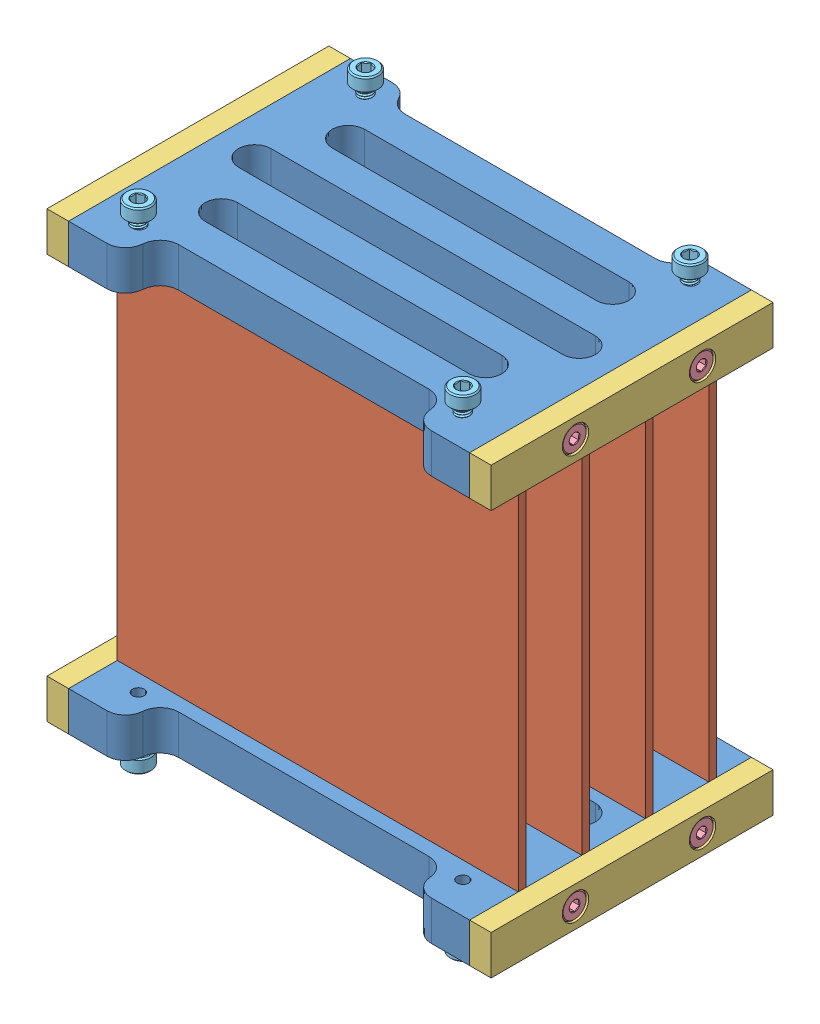
SolidWorks assembly STACK_SHELVES_ASSEMBLY, configuration Default. Lengths in mm.
Overall size (95.8 106.09 60.8).
26 component instances, 5 part files, 36 mates.
Components (placement in the parent):
- PCB_SHELF-1: PCB_SHELF [Default] at (-4.1696 1.9377 23.7027) x (0 1 0) z (1 0 0) size (8.5 60.8 86.5)
- FAKE_PCB-1: FAKE_PCB [Default] at (82.3304 4.4377 31.2027) x (0 1 0) z (1 0 0) size (91 1.7 86.5)
- FAKE_PCB-2: FAKE_PCB [Default] at (82.3304 4.4377 44.9027) x (0 1 0) z (1 0 0) size (91 1.7 86.5)
- FAKE_PCB-3: FAKE_PCB [Default] at (82.3304 4.4377 58.6027) x (0 1 0) z (1 0 0) size (91 1.7 86.5)
- FAKE_PCB-4: FAKE_PCB [Default] at (82.3304 4.3377 72.3027) x (0 1 0) z (1 0 0) size (91 1.7 86.5)
- PCB_SHELF-2: PCB_SHELF [Default] at (82.3304 97.7377 23.7027) x (0 -1 0) z (-1 0 0) size (8.5 60.8 86.5)
- PCB_SHELF_ENDS-1: PCB_SHELF_ENDS [Default] at (-4.1696 97.7377 84.5027) x (0 -1 0) z (-1 0 0) size (8.5 60.8 4.65)
- PCB_SHELF_ENDS-2: PCB_SHELF_ENDS [Default] at (-4.1696 10.4377 84.5027) x (0 -1 0) z (-1 0 0) size (8.5 60.8 4.65)
- PCB_SHELF_ENDS-3: PCB_SHELF_ENDS [Default] at (82.3304 89.2377 84.5027) x (0 1 0) z (1 0 0) size (8.5 60.8 4.65)
- PCB_SHELF_ENDS-4: PCB_SHELF_ENDS [Default] at (82.3304 1.9377 84.5027) x (0 1 0) z (1 0 0) size (8.5 60.8 4.65)
- M3_LP_6MM_90666A103_TYPE 316 SS LOW PROFILE SOCKET HEAD CAP SCREW-1: M3_LP_6MM_90666A103_TYPE 316 SS LOW PROFILE SOCKET HEAD CAP SCREW [90666A103] at (78.7804 6.1877 66.3027) x (0 -0.137884 0.990448) z (-1 0 0) size (5.5 5.5 8.16)
- M3_6MM_91292A111_TYPE 18-8 SS SOCKET HEAD CAP SCREW-1: M3_6MM_91292A111_TYPE 18-8 SS SOCKET HEAD CAP SCREW [91292A111] at (74.0804 93.7377 77.7027) x (0.999989 0 -0.00475) z (0 -1 0) size (5.5 5.5 9.19)
- M3_LP_6MM_90666A103_TYPE 316 SS LOW PROFILE SOCKET HEAD CAP SCREW-9: M3_LP_6MM_90666A103_TYPE 316 SS LOW PROFILE SOCKET HEAD CAP SCREW [90666A103] at (78.7804 6.1877 38.9027) x (0 0 1) z (-1 0 0) size (5.5 5.5 8.16)
- M3_LP_6MM_90666A103_TYPE 316 SS LOW PROFILE SOCKET HEAD CAP SCREW-3: M3_LP_6MM_90666A103_TYPE 316 SS LOW PROFILE SOCKET HEAD CAP SCREW [90666A103] at (78.7804 93.4877 66.3027) x (0 0.137884 0.990448) z (-1 0 0) size (5.5 5.5 8.16)
- M3_LP_6MM_90666A103_TYPE 316 SS LOW PROFILE SOCKET HEAD CAP SCREW-5: M3_LP_6MM_90666A103_TYPE 316 SS LOW PROFILE SOCKET HEAD CAP SCREW [90666A103] at (-0.6196 6.1877 66.3027) x (0 -0.137884 0.990448) z (1 0 0) size (5.5 5.5 8.16)
- M3_LP_6MM_90666A103_TYPE 316 SS LOW PROFILE SOCKET HEAD CAP SCREW-7: M3_LP_6MM_90666A103_TYPE 316 SS LOW PROFILE SOCKET HEAD CAP SCREW [90666A103] at (-0.6196 93.4877 66.3027) x (0 0.137884 0.990448) z (1 0 0) size (5.5 5.5 8.16)
- M3_6MM_91292A111_TYPE 18-8 SS SOCKET HEAD CAP SCREW-3: M3_6MM_91292A111_TYPE 18-8 SS SOCKET HEAD CAP SCREW [91292A111] at (4.0804 93.7377 77.7027) x (-0.999989 0 -0.00475) z (0 -1 0) size (5.5 5.5 9.19)
- M3_6MM_91292A111_TYPE 18-8 SS SOCKET HEAD CAP SCREW-5: M3_6MM_91292A111_TYPE 18-8 SS SOCKET HEAD CAP SCREW [91292A111] at (74.0804 5.9377 77.7027) x (0.999989 0 -0.00475) z (0 1 0) size (5.5 5.5 9.19)
- M3_6MM_91292A111_TYPE 18-8 SS SOCKET HEAD CAP SCREW-7: M3_6MM_91292A111_TYPE 18-8 SS SOCKET HEAD CAP SCREW [91292A111] at (4.0804 5.9377 77.7027) x (-0.999989 0 -0.00475) z (0 1 0) size (5.5 5.5 9.19)
- M3_LP_6MM_90666A103_TYPE 316 SS LOW PROFILE SOCKET HEAD CAP SCREW-10: M3_LP_6MM_90666A103_TYPE 316 SS LOW PROFILE SOCKET HEAD CAP SCREW [90666A103] at (78.7804 93.4877 38.9027) x (0 0 1) z (-1 0 0) size (5.5 5.5 8.16)
- M3_LP_6MM_90666A103_TYPE 316 SS LOW PROFILE SOCKET HEAD CAP SCREW-11: M3_LP_6MM_90666A103_TYPE 316 SS LOW PROFILE SOCKET HEAD CAP SCREW [90666A103] at (-0.6196 6.1877 38.9027) x (0 0 1) z (1 0 0) size (5.5 5.5 8.16)
- M3_LP_6MM_90666A103_TYPE 316 SS LOW PROFILE SOCKET HEAD CAP SCREW-12: M3_LP_6MM_90666A103_TYPE 316 SS LOW PROFILE SOCKET HEAD CAP SCREW [90666A103] at (-0.6196 93.4877 38.9027) x (0 0 1) z (1 0 0) size (5.5 5.5 8.16)
- M3_6MM_91292A111_TYPE 18-8 SS SOCKET HEAD CAP SCREW-9: M3_6MM_91292A111_TYPE 18-8 SS SOCKET HEAD CAP SCREW [91292A111] at (74.0804 93.7377 28.7027) x (-0.982447 0 -0.186539) z (0 -1 0) size (5.5 5.5 9.19)
- M3_6MM_91292A111_TYPE 18-8 SS SOCKET HEAD CAP SCREW-10: M3_6MM_91292A111_TYPE 18-8 SS SOCKET HEAD CAP SCREW [91292A111] at (4.0804 93.7377 28.7027) x (0.982447 0 -0.186539) z (0 -1 0) size (5.5 5.5 9.19)
- M3_6MM_91292A111_TYPE 18-8 SS SOCKET HEAD CAP SCREW-11: M3_6MM_91292A111_TYPE 18-8 SS SOCKET HEAD CAP SCREW [91292A111] at (74.0804 5.9377 28.7027) x (-0.982447 0 -0.186539) z (0 1 0) size (5.5 5.5 9.19)
- M3_6MM_91292A111_TYPE 18-8 SS SOCKET HEAD CAP SCREW-12: M3_6MM_91292A111_TYPE 18-8 SS SOCKET HEAD CAP SCREW [91292A111] at (4.0804 -3.1627 28.7027) x (0.982447 0 -0.186539) z (0 -1 0) size (5.5 5.5 9.19)
Mates (geometry in assembly coordinates):
- Coincident10: coincident anti-aligned: plane of PCB_SHELF-1 through (82.3304 4.4377 32.9027) normal (0 1 0); plane of FAKE_PCB-1 through (82.3304 4.4377 32.9027) normal (0 -1 0)
- Coincident11: coincident anti-aligned: plane of PCB_SHELF-1 through (82.3304 4.4377 31.2027) normal (0 0 1); plane of FAKE_PCB-1 through (82.3304 4.4377 31.2027) normal (0 0 -1)
- Coincident12: coincident aligned: plane of PCB_SHELF-1 through (82.3304 1.9377 23.7027) normal (1 0 0); plane of FAKE_PCB-1 through (82.3304 95.4377 32.9027) normal (1 0 0)
- Coincident13: coincident anti-aligned: plane of PCB_SHELF-1 through (82.3304 4.4377 46.6027) normal (0 1 0); plane of FAKE_PCB-2 through (82.3304 4.4377 46.6027) normal (0 -1 0)
- Coincident14: coincident anti-aligned: plane of PCB_SHELF-1 through (82.3304 4.4377 44.9027) normal (0 0 1); plane of FAKE_PCB-2 through (82.3304 4.4377 44.9027) normal (0 0 -1)
- Coincident15: coincident aligned: plane of PCB_SHELF-1 through (-4.1696 1.9377 23.7027) normal (-1 0 0); plane of FAKE_PCB-2 through (-4.1696 4.4377 46.6027) normal (-1 0 0)
- Coincident16: coincident anti-aligned: plane of PCB_SHELF-1 through (82.3304 4.4377 60.3027) normal (0 1 0); plane of FAKE_PCB-3 through (82.3304 4.4377 60.3027) normal (0 -1 0)
- Coincident17: coincident anti-aligned: plane of PCB_SHELF-1 through (82.3304 4.4377 58.6027) normal (0 0 1); plane of FAKE_PCB-3 through (82.3304 4.4377 58.6027) normal (0 0 -1)
- Coincident18: coincident aligned: plane of PCB_SHELF-1 through (-4.1696 1.9377 23.7027) normal (-1 0 0); plane of FAKE_PCB-3 through (-4.1696 4.4377 60.3027) normal (-1 0 0)
- Coincident19: coincident anti-aligned: plane of PCB_SHELF-1 through (82.3304 4.3377 74.0027) normal (0 1 0); plane of FAKE_PCB-4 through (82.3304 4.3377 74.0027) normal (0 -1 0)
- Coincident20: coincident anti-aligned: plane of PCB_SHELF-1 through (82.3304 4.3377 72.3027) normal (0 0 1); plane of FAKE_PCB-4 through (82.3304 4.3377 72.3027) normal (0 0 -1)
- Coincident21: coincident aligned: plane of PCB_SHELF-1 through (-4.1696 1.9377 23.7027) normal (-1 0 0); plane of FAKE_PCB-4 through (-4.1696 4.3377 74.0027) normal (-1 0 0)
- Coincident22: coincident anti-aligned: plane of FAKE_PCB-4 through (-4.1696 95.3377 74.0027) normal (0 1 0); plane of PCB_SHELF-2 through (-4.1696 95.3377 74.0027) normal (0 -1 0)
- Coincident23: coincident aligned: plane of FAKE_PCB-4 through (82.3304 95.3377 74.0027) normal (1 0 0); plane of PCB_SHELF-2 through (82.3304 97.7377 23.7027) normal (1 0 0)
- Coincident24: coincident aligned: plane of FAKE_PCB-1 through (82.3304 95.4377 32.9027) normal (1 0 0); plane of PCB_SHELF-2 through (82.3304 97.7377 23.7027) normal (1 0 0)
- Coincident25: coincident anti-aligned: plane of FAKE_PCB-1 through (82.3304 4.4377 32.9027) normal (0 0 1); plane of PCB_SHELF-2 through (-4.1696 89.2377 32.9027) normal (0 0 -1)
- Concentric1: concentric aligned: cylinder of PCB_SHELF-1 through (82.3304 6.1877 66.3027) axis (1 0 0) radius 1.25; cylinder of PCB_SHELF_ENDS-4 through (86.9804 6.1877 66.3027) axis (1 0 0) radius 1.5
- Coincident26: coincident anti-aligned: plane of PCB_SHELF-1 through (82.3304 1.9377 23.7027) normal (1 0 0); plane of PCB_SHELF_ENDS-4 through (82.3304 1.9377 84.5027) normal (-1 0 0)
- Concentric2: concentric aligned: cylinder of PCB_SHELF-1 through (82.3304 6.1877 38.9027) axis (1 0 0) radius 1.25; cylinder of PCB_SHELF_ENDS-4 through (86.9804 6.1877 38.9027) axis (1 0 0) radius 1.5
- Coincident27: coincident anti-aligned: plane of PCB_SHELF-2 through (82.3304 97.7377 23.7027) normal (1 0 0); plane of PCB_SHELF_ENDS-3 through (82.3304 89.2377 84.5027) normal (-1 0 0)
- Concentric3: concentric aligned: cylinder of PCB_SHELF-2 through (82.3304 93.4877 66.3027) axis (1 0 0) radius 1.25; cylinder of PCB_SHELF_ENDS-3 through (86.9804 93.4877 66.3027) axis (1 0 0) radius 1.5
- Concentric4: concentric aligned: cylinder of PCB_SHELF-2 through (82.3304 93.4877 38.9027) axis (1 0 0) radius 1.25; cylinder of PCB_SHELF_ENDS-3 through (86.9804 93.4877 38.9027) axis (1 0 0) radius 1.5
- Coincident28: coincident anti-aligned: plane of PCB_SHELF-1 through (-4.1696 1.9377 23.7027) normal (-1 0 0); plane of PCB_SHELF_ENDS-2 through (-4.1696 10.4377 84.5027) normal (1 0 0)
- Concentric5: concentric aligned: cylinder of PCB_SHELF-1 through (-4.1696 6.1877 66.3027) axis (-1 0 0) radius 1.25; cylinder of PCB_SHELF_ENDS-2 through (-8.8196 6.1877 66.3027) axis (-1 0 0) radius 1.5
- Concentric6: concentric aligned: cylinder of PCB_SHELF-1 through (-4.1696 6.1877 38.9027) axis (-1 0 0) radius 1.25; cylinder of PCB_SHELF_ENDS-2 through (-8.8196 6.1877 38.9027) axis (-1 0 0) radius 1.5
- Coincident29: coincident anti-aligned: plane of PCB_SHELF-2 through (-4.1696 97.7377 23.7027) normal (-1 0 0); plane of PCB_SHELF_ENDS-1 through (-4.1696 97.7377 84.5027) normal (1 0 0)
- Concentric7: concentric aligned: cylinder of PCB_SHELF-2 through (-4.1696 93.4877 66.3027) axis (-1 0 0) radius 1.25; cylinder of PCB_SHELF_ENDS-1 through (-8.8196 93.4877 66.3027) axis (-1 0 0) radius 1.5
- Concentric8: concentric aligned: cylinder of PCB_SHELF-2 through (-4.1696 93.4877 38.9027) axis (-1 0 0) radius 1.25; cylinder of PCB_SHELF_ENDS-1 through (-8.8196 93.4877 38.9027) axis (-1 0 0) radius 1.5
- Concentric9: concentric anti-aligned: circle of PCB_SHELF_ENDS-4; circle of M3_LP_6MM_90666A103_TYPE 316 SS LOW PROFILE SOCKET HEAD CAP SCREW-1
- Coincident31: coincident anti-aligned: plane of PCB_SHELF_ENDS-4 through (84.7804 6.1877 66.3027) normal (1 0 0); plane of M3_LP_6MM_90666A103_TYPE 316 SS LOW PROFILE SOCKET HEAD CAP SCREW-1 through (84.7804 6.1877 66.3027) normal (-1 0 0)
- Concentric10: concentric anti-aligned: circle of PCB_SHELF-2; circle of M3_6MM_91292A111_TYPE 18-8 SS SOCKET HEAD CAP SCREW-1
- Distance1: distance = 2 mm anti-aligned: plane of PCB_SHELF-2 through (-4.1696 97.7377 23.7027) normal (0 1 0); plane of M3_6MM_91292A111_TYPE 18-8 SS SOCKET HEAD CAP SCREW-1 through (74.0804 99.7377 77.7027) normal (0 -1 0)
- Concentric11: concentric anti-aligned: circle of PCB_SHELF-1; circle of M3_LP_6MM_90666A103_TYPE 316 SS LOW PROFILE SOCKET HEAD CAP SCREW-9
- Coincident32: coincident anti-aligned: plane of PCB_SHELF_ENDS-4 through (84.7804 6.1877 38.9027) normal (1 0 0); plane of M3_LP_6MM_90666A103_TYPE 316 SS LOW PROFILE SOCKET HEAD CAP SCREW-9 through (84.7804 6.1877 38.9027) normal (-1 0 0)
- Distance2: distance = 2 mm anti-aligned: plane of PCB_SHELF-2 through (-4.1696 97.7377 23.7027) normal (0 1 0); plane of M3_6MM_91292A111_TYPE 18-8 SS SOCKET HEAD CAP SCREW-9 through (74.0804 99.7377 28.7027) normal (0 -1 0)
- Concentric12: concentric anti-aligned: circle of PCB_SHELF-2; circle of M3_6MM_91292A111_TYPE 18-8 SS SOCKET HEAD CAP SCREW-9
